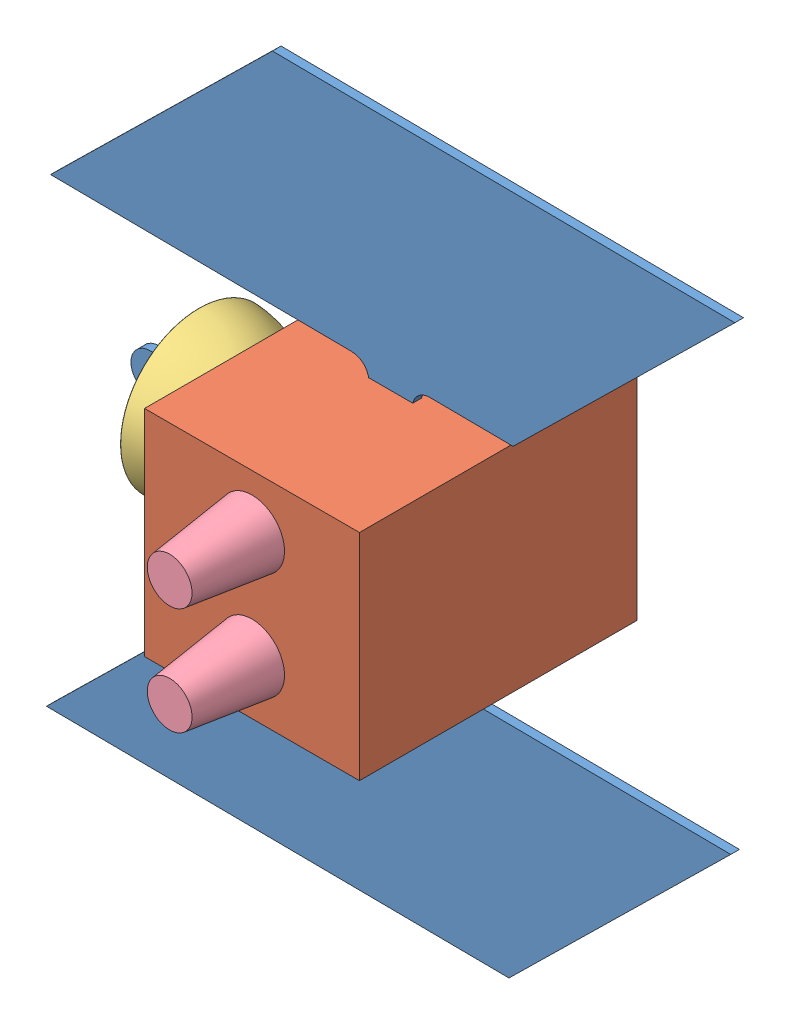
SolidWorks assembly Full_Sat, configuration Default. Lengths in mm.
Overall size (1008.83 1008.83 527.05).
5 component instances, 4 part files, 63 mates.
Components (placement in the parent):
- wings-1: wings [Default] x (-0.008873 -0.999961 0) z (0.999961 -0.008873 0) size (1000 12.7 1000)
- box-1: box [Default] at (-152.4 -152.4 203.2) x (0 1 0) z (-1 0 0) size (314.96 406.4 314.96)
- IKEA BLANDA BLANK SERVING BOWL-1: IKEA BLANDA BLANK SERVING BOWL [Default] at (-157.48 0 -6.35) x (0 0 1) z (0 -1 0) size (229.94 130 229.94)
- cup-1: cup [Default] at (0 78.74 203.2) x (1 0 0) z (0 -1 0) size (95.25 120.65 95.25)
- cup-2: cup [Default] at (0 -78.74 203.2) x (1 0 0) z (0 -1 0) size (95.25 120.65 95.25)
Mates (geometry in assembly coordinates):
- Concentric1: concentric anti-aligned: circle of ?; circle of wings-1
- Coincident10: coincident anti-aligned: circle of ?; circle of ?
- Coincident11: coincident anti-aligned: circle of ?; circle of ?
- Coincident16: coincident anti-aligned: circle of ?; circle of ?
- Coincident22: coincident anti-aligned: circle of ?; circle of ?
- Coincident23: coincident aligned: circle of ?; circle of ?
- Concentric3: concentric anti-aligned: cylinder of ? through (497.7293 632.6875 775.66) axis (0 0 1) radius 3.175; cylinder of ? through (497.7293 632.6875 775.66) axis (0 0 -1) radius 3.175
- Parallel5: parallel aligned: plane of ? through (533.8608 632.6875 350.21) normal (1 0 0); plane of assembly through (0 0 0) normal (1 0 0)
- Parallel6: parallel aligned: plane of ? through (533.8608 632.6875 782.01) normal (1 0 0); plane of assembly through (0 0 0) normal (1 0 0)
- Concentric8: concentric anti-aligned: cylinder of ? through (533.8608 668.819 343.86) axis (0 0 1) radius 3.175; cylinder of ? through (533.8608 668.819 315.0564) axis (0 0 -1) radius 6.4897
- Coincident32: coincident anti-aligned: plane of ? through (533.8608 632.6875 343.86) normal (0 0 -1); plane of ? through (533.8608 671.5622 343.86) normal (0 0 1)
- Concentric9: concentric anti-aligned: cylinder of ? through (497.7293 632.6875 343.86) axis (0 0 1) radius 3.175; cylinder of ? through (497.7293 632.6875 315.0564) axis (0 0 -1) radius 6.4897
- Coincident33: coincident anti-aligned: plane of ? through (533.8608 632.6875 343.86) normal (0 0 -1); plane of ? through (497.7293 635.4307 343.86) normal (0 0 1)
- Concentric10: concentric anti-aligned: cylinder of ? through (533.8608 596.556 343.86) axis (0 0 1) radius 3.175; cylinder of ? through (533.8608 596.556 315.0564) axis (0 0 -1) radius 6.4897
- Coincident34: coincident anti-aligned: plane of ? through (533.8608 632.6875 343.86) normal (0 0 -1); plane of ? through (533.8608 599.2992 343.86) normal (0 0 1)
- Concentric11: concentric anti-aligned: cylinder of ? through (569.9923 632.6875 343.86) axis (0 0 1) radius 3.175; cylinder of ? through (569.9923 632.6875 315.0564) axis (0 0 -1) radius 6.4897
- Coincident35: coincident anti-aligned: plane of ? through (533.8608 632.6875 343.86) normal (0 0 -1); plane of ? through (569.9923 635.4307 343.86) normal (0 0 1)
- Concentric12: concentric aligned: cylinder of ? through (569.9923 632.6875 350.21) axis (0 0 1) radius 3.175; cylinder of ? through (569.9923 632.6875 338.5329) axis (0 0 1) radius 3.175
- Coincident36: coincident anti-aligned: plane of ? through (533.8608 632.6875 357.83) normal (0 0 1); plane of ? through (569.9923 626.2717 357.83) normal (0 0 -1)
- Concentric13: concentric aligned: cylinder of ? through (533.8608 596.556 350.21) axis (0 0 1) radius 3.175; cylinder of ? through (533.8608 596.556 338.5329) axis (0 0 1) radius 3.175
- Coincident37: coincident anti-aligned: plane of ? through (533.8608 632.6875 357.83) normal (0 0 1); plane of ? through (533.8608 590.1402 357.83) normal (0 0 -1)
- Concentric14: concentric aligned: cylinder of ? through (533.8608 668.819 350.21) axis (0 0 1) radius 3.175; cylinder of ? through (533.8608 668.819 338.5329) axis (0 0 1) radius 3.175
- Coincident38: coincident anti-aligned: plane of ? through (533.8608 632.6875 357.83) normal (0 0 1); plane of ? through (533.8608 662.4032 357.83) normal (0 0 -1)
- Concentric15: concentric aligned: cylinder of ? through (497.7293 632.6875 350.21) axis (0 0 1) radius 3.175; cylinder of ? through (497.7293 632.6875 338.5329) axis (0 0 1) radius 3.175
- Coincident39: coincident anti-aligned: plane of ? through (533.8608 632.6875 357.83) normal (0 0 1); plane of ? through (497.7293 639.1033 357.83) normal (0 0 -1)
- Coincident44: coincident anti-aligned: circle of ?; circle of ?
- Coincident46: coincident aligned: circle of ?; circle of box-1
- Coincident47: coincident aligned: circle of ?; circle of box-1
- Concentric20: concentric anti-aligned: cylinder of box-1 through (569.9923 632.6875 787.09) axis (0 0 -1) radius 3.175; cylinder of ? through (569.9923 632.6875 815.8936) axis (0 0 1) radius 6.4897
- Coincident48: coincident anti-aligned: plane of box-1 through (381.4608 480.2875 787.09) normal (0 0 1); plane of ? through (569.9923 635.4307 787.09) normal (0 0 -1)
- Concentric21: concentric anti-aligned: cylinder of box-1 through (533.8608 596.556 787.09) axis (0 0 -1) radius 3.175; cylinder of ? through (533.8608 596.556 815.8936) axis (0 0 1) radius 6.4897
- Coincident49: coincident anti-aligned: plane of box-1 through (381.4608 480.2875 787.09) normal (0 0 1); plane of ? through (533.8608 599.2992 787.09) normal (0 0 -1)
- Concentric22: concentric anti-aligned: cylinder of box-1 through (497.7293 632.6875 787.09) axis (0 0 -1) radius 3.175; cylinder of ? through (497.7293 632.6875 815.8936) axis (0 0 1) radius 6.4897
- Coincident50: coincident anti-aligned: plane of box-1 through (381.4608 480.2875 787.09) normal (0 0 1); plane of ? through (497.7293 635.4307 787.09) normal (0 0 -1)
- Concentric23: concentric anti-aligned: cylinder of box-1 through (533.8608 668.819 787.09) axis (0 0 -1) radius 3.175; cylinder of ? through (533.8608 668.819 815.8936) axis (0 0 1) radius 6.4897
- Coincident51: coincident anti-aligned: plane of box-1 through (381.4608 480.2875 787.09) normal (0 0 1); plane of ? through (534.9116 666.285 787.09) normal (0 0 -1)
- Concentric24: concentric aligned: cylinder of ? through (533.8608 596.556 775.66) axis (0 0 -1) radius 3.175; cylinder of ? through (533.8608 596.556 787.3371) axis (0 0 -1) radius 3.175
- Coincident52: coincident anti-aligned: plane of ? through (533.8608 632.6875 768.04) normal (0 0 -1); plane of ? through (531.4032 602.4825 768.04) normal (0 0 1)
- Concentric25: concentric aligned: cylinder of ? through (497.7293 632.6875 775.66) axis (0 0 -1) radius 3.175; cylinder of ? through (497.7293 632.6875 787.3371) axis (0 0 -1) radius 3.175
- Coincident53: coincident anti-aligned: plane of ? through (533.8608 632.6875 768.04) normal (0 0 -1); plane of ? through (500.1869 626.7611 768.04) normal (0 0 1)
- Concentric26: concentric aligned: cylinder of ? through (569.9923 632.6875 775.66) axis (0 0 -1) radius 3.175; cylinder of ? through (569.9923 632.6875 787.3371) axis (0 0 -1) radius 3.175
- Coincident54: coincident anti-aligned: plane of ? through (533.8608 632.6875 768.04) normal (0 0 -1); plane of ? through (567.5347 638.614 768.04) normal (0 0 1)
- Concentric27: concentric aligned: cylinder of ? through (533.8608 668.819 775.66) axis (0 0 -1) radius 3.175; cylinder of ? through (533.8608 668.819 787.3371) axis (0 0 -1) radius 3.175
- Coincident55: coincident anti-aligned: plane of ? through (533.8608 632.6875 768.04) normal (0 0 -1); plane of ? through (536.3184 662.8926 768.04) normal (0 0 1)
- Parallel7: parallel anti-aligned: line of ? through (498.0817 484.547 566.11) axis (0 1 0); line of wings-1 through (502.112 620.2571 566.11) axis (0 -1 0)
- Coincident60: coincident anti-aligned: plane of ? through (533.8608 232.6375 566.11) normal (0 0 1); plane of wings-1 through (533.8608 632.6875 566.11) normal (0 0 -1)
- Coincident61: coincident aligned: line of wings-1 through (590.7842 454.3824 578.81) axis (0.999961 -0.008873 0); line of ? through (570.3392 454.5638 578.81) axis (0.999961 -0.008873 0)
- Coincident62: coincident aligned: line of wings-1 through (1032.2636 450.465 578.81) axis (-0.713353 -0.700805 0); line of ? through (1032.2636 450.465 578.81) axis (-0.713353 -0.700805 0)
- Coincident63: coincident aligned: line of wings-1 through (1038.2776 1128.2313 578.81) axis (-0.713353 -0.700805 0); line of ? through (1038.2776 1128.2313 578.81) axis (-0.713353 -0.700805 0)
- Coincident64: coincident aligned: line of wings-1 through (360.5113 1134.2454 578.81) axis (0.999961 -0.008873 0); line of ? through (576.3533 1132.3302 578.81) axis (0.999961 -0.008873 0)
- Coincident65: coincident anti-aligned: plane of box-1 through (-157.48 -152.4 1018.9148) normal (-1 0 0); plane of IKEA BLANDA BLANK SERVING BOWL-1 through (-157.48 0 1215.7648) normal (1 0 0)
- Coincident68: coincident anti-aligned: plane of wings-1 through (0 0 1209.4148) normal (0 0 -1); plane of IKEA BLANDA BLANK SERVING BOWL-1 through (-287.48 12.7116 1209.4148) normal (0 0 1)
- Coincident69: coincident anti-aligned: plane of box-1 through (381.4608 480.2875 787.09) normal (0 0 1); plane of ? through (533.8608 553.9475 787.09) normal (0 0 -1)
- Coincident70: coincident anti-aligned: plane of box-1 through (381.4608 480.2875 787.09) normal (0 0 1); plane of ? through (533.8608 711.4275 787.09) normal (0 0 -1)
- Concentric28: concentric aligned: circle of ?
- Concentric29: concentric anti-aligned: circle of ?
- Lock1: lock: unknown of wings-1; unknown of box-1
- Lock2: lock: unknown of box-1; unknown of IKEA BLANDA BLANK SERVING BOWL-1
- Lock3: lock: unknown of box-1; unknown of cup-1
- Lock4: lock: unknown of box-1; unknown of cup-2
- Distance1: distance = 157.48 mm aligned: plane of box-1 through (-152.4 157.48 -203.2) normal (0 1 0); plane of assembly
- Distance2: distance = 157.48 mm anti-aligned: plane of box-1 through (-157.48 -152.4 -203.2) normal (-1 0 0); plane of assembly
- Distance3: distance = 203.2 mm anti-aligned: plane of box-1 through (-152.4 -152.4 -203.2) normal (0 0 -1); plane of assembly
